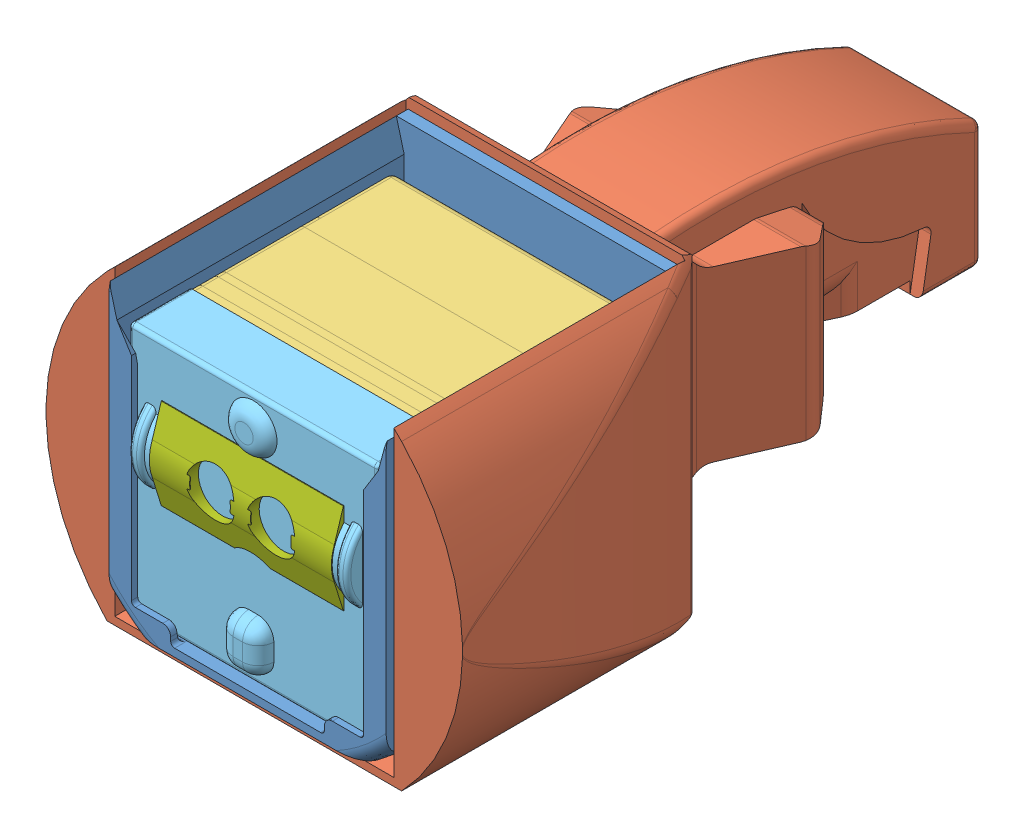
SolidWorks assembly Alice_Normal_Asm, configuration Default. Lengths in mm.
Overall size (53.26 46.21 86.3).
34 component instances, 31 part files, 6 mates.
Components (placement in the parent):
- docking-base_LED_front-1: docking-base_LED_front [Default] at (14.7802 24.7468 15.8776) size (35.6 37.27 42.93)
- Part1^Alice_Normal_Asm-1: Part1^Alice_Normal_Asm [Default] at origin (virtual)
- Alice_Base-1: Alice_Base [Default] at (14.6302 21.6337 15.3776) x (-1 0 0) z (0 1 0) size (53.26 84.13 46.21)
- servoShell-1: servoShell [Default] at (-4.3586 11.1425 41.7797) x (-1 0 0) z (0 0 -1) size (31.8 32.3 38.65)
  - cover_MAIN-1: cover_MAIN [Default] at (-141.0888 46.4042 -3.2479) size (31.8 31.8 29)
  - Part1^servoShell-1: Part1^servoShell [Default] at origin (virtual)
  - servo-2: servo [Default] at (-7.7138 45.2792 -40.6729) x (0 0 1) z (-1 0 0) size (23.76 12.15 15) (hidden)
    - servo.stp-1: servo.stp [Default] at origin size (23.76 12.15 15)
      - Block 01.stp-1: Block 01.stp [Default] at (49.925 -22.475 8.625) x (0 0 -1) z (-1 0 0) size (4.01 4.01 15.31)
      - Document.stp-1: Document.stp [Default] at origin size (18 0.5 15)
      - Document-0.stp-1: Document-0.stp [Default] at origin size (2.7 1 1)
      - Document-1.stp-1: Document-1.stp [Default] at origin size (14.95 4.5 4.8)
      - Document-2.stp-1: Document-2.stp [Default] at origin size (0.9 6.9 6.9)
      - Document-3.stp-1: Document-3.stp [Default] at origin size (5 0.51 0.51)
      - Document-4.stp-1: Document-4.stp [Default] at origin size (3 7.75 0.9)
      - Document-5.stp-1: Document-5.stp [Default] at origin size (5 0.51 0.51)
      - Document-6.stp-1: Document-6.stp [Default] at origin size (5 0.51 0.51)
      - Document-7.stp-1: Document-7.stp [Default] at origin size (1.2 2.3 2.3)
      - Document-8.stp-1: Document-8.stp [Default] at origin size (2.2 2.2 2.2)
      - Document-9.stp-1: Document-9.stp [Default] at origin size (5 1.4 4)
      - Document-10.stp-1: Document-10.stp [Default] at origin size (0.6 1 1)
      - Document-11.stp-1: Document-11.stp [Default] at origin size (0.6 1 1)
      - Document-12.stp-1: Document-12.stp [Default] at origin size (0.6 1 1)
      - Document-13.stp-1: Document-13.stp [Default] at origin size (0.6 1 1)
      - Document-14.stp-1: Document-14.stp [Default] at origin size (0.6 1 1)
      - Document-15.stp-1: Document-15.stp [Default] at origin size (0.6 1 1)
      - Document-16.stp-1: Document-16.stp [Default] at origin size (0.6 1 1)
      - Document-17.stp-1: Document-17.stp [Default] at origin size (0.6 1 1)
  - Part2^servoShell-1: Part2^servoShell [Default] at (-0.1819 25.3042 1.3124) x (-1 0 0) z (0 -1 0) size (25.28 19.6 2.5) (hidden)
  - Part3^servoShell-1: Part3^servoShell [Default] at (-141.0888 46.4042 21.7521) size (6 6.75 15.8)
  - toioBase^servoShell-1: toioBase^servoShell [Default] at (-141.0888 46.4042 -4.2479) x (-1 0 0) z (0 0 -1) size (31.8 31.8 9.65) (virtual)
  - Part4^servoShell-1: Part4^servoShell [Default] at (-141.0888 -5.4958 -3.2479) x (-1 0 0) z (0 -1 0) size (5.75 3.25 1.5) (virtual)
  - Magnet Mount_3disc^servoShell-1: Magnet Mount_3disc^servoShell [Default] at (-141.0888 46.4042 -11.8979) x (-1 0 0) z (0 0 -1) size (14.6 7.75 1.41) (hidden, virtual)
  - MagnetMount_2disc^servoShell-2: MagnetMount_2disc^servoShell [Default] at (-26.4888 46.4042 -4.2479) x (0 0 -1) z (1 0 0) size (1.62 11.6 23.2) (virtual)
Mates (geometry in assembly coordinates):
- Coincident3: coincident: plane of docking-base_LED_front-1 through (14.7802 24.7468 16.3776) normal (0 0 -1); plane of Alice_Base-1 through (14.6302 21.6337 16.3776) normal (0 0 1)
- Coincident5: coincident: plane of docking-base_LED_front-1 through (18.7302 20.7968 11.8776) normal (0 -1 0); plane of Alice_Base-1 through (18.7302 20.7968 11.3776) normal (0 1 0)
- Coincident6: coincident: plane of docking-base_LED_front-1 through (18.7302 28.6968 11.8776) normal (1 0 0); plane of Alice_Base-1 through (18.7302 28.9968 11.3776) normal (-1 0 0)
- Distance1: distance = 0.1 mm: plane of servoShell-1/toioBase^servoShell-1 through (136.7302 57.5468 53.6776) normal (0 0 1); plane of docking-base_LED_front-1 through (-0.8698 6.1468 53.5776) normal (0 0 -1)
- Distance2: distance = 0.5 mm: plane of servoShell-1/cover_MAIN-1 through (30.6302 5.6468 45.0276) normal (0 -1 0); plane of docking-base_LED_front-1 through (-0.8698 5.1468 -44.0114) normal (0 1 0)
- Distance3: distance = 0.7 mm: plane of servoShell-1/cover_MAIN-1 through (-1.1698 5.6468 45.0276) normal (-1 0 0); plane of docking-base_LED_front-1 through (-1.8698 37.6833 -44.0114) normal (1 0 0)
